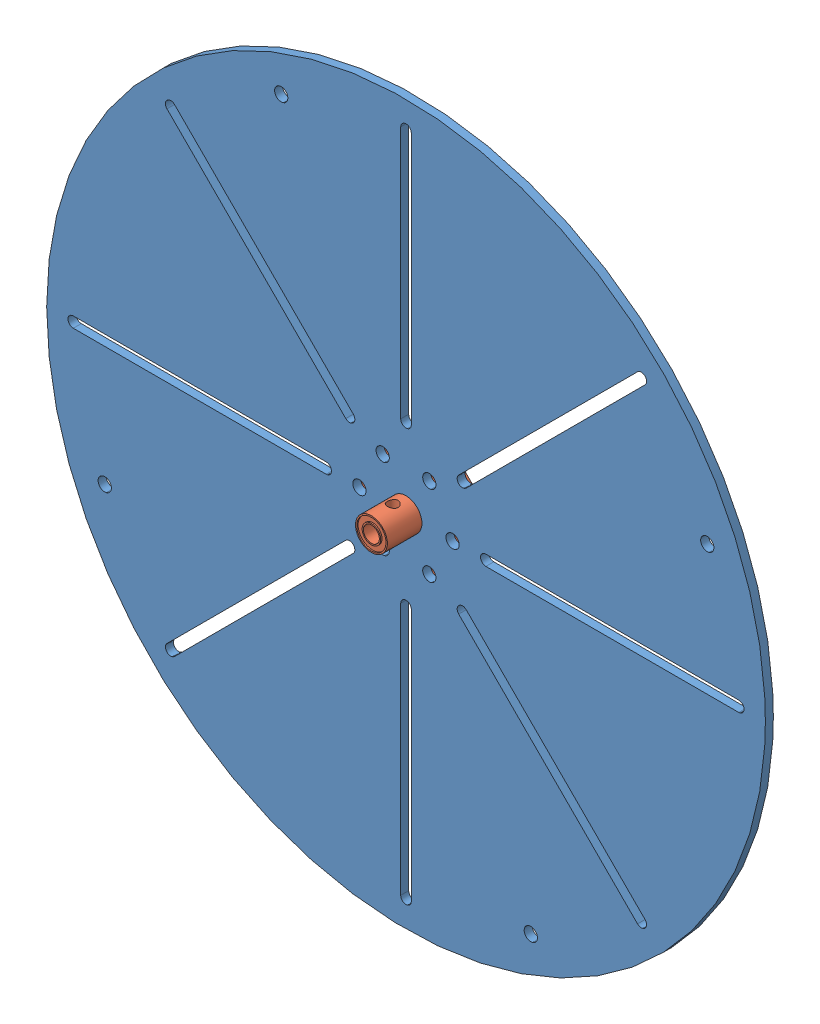
SolidWorks assembly faceplate-sub, configuration Default. Lengths in mm.
Overall size (270 270 20).
2 component instances, 2 part files, 5 mates.
Components (placement in the parent):
- facePlate-2.0-1: facePlate-2.0 [Default] at origin size (270 270 3)
- flange-coupling-1: flange-coupling [Default] x (-1 0 0) z (0 0 -1) size (47 47 20)
Mates (geometry in assembly coordinates):
- Coincident1: coordinate: point of facePlate-2.0-1
- Parallel1: parallel aligned: plane of facePlate-2.0-1 through (0 0 0) normal (0 1 0)
- Concentric1: concentric: cylinder of flange-coupling-1 through (0 0 -4) axis (0 0 1) radius 3; cylinder of facePlate-2.0-1 through (0 0 3) axis (0 0 -1) radius 135
- Concentric2: concentric aligned: cylinder of flange-coupling-1 through (8.75 15.1554 16) axis (0 0 -1) radius 2.5; cylinder of facePlate-2.0-1 through (8.75 15.1554 3) axis (0 0 -1) radius 2.5
- Coincident2: coincident: plane of facePlate-2.0-1 through (0 0 0) normal (0 0 -1); plane of flange-coupling-1 through (0 0 0) normal (0 0 1)
